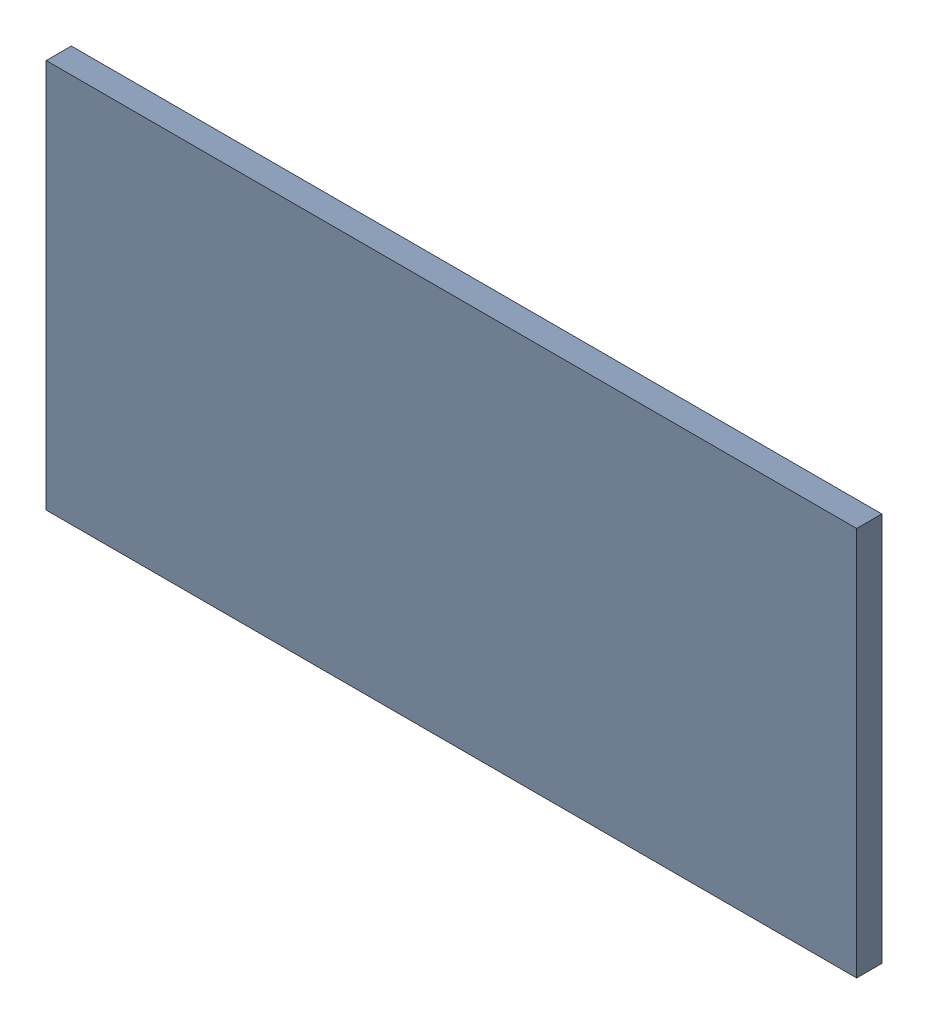
SolidWorks assembly Pad ADXL345-14(23.098mm,57mm) on Top Layer, configuration Predeterminado. Lengths in mm.
Overall size (1.14 0.55 0.04).
2 component instances, 1 part files, 0 mates.
Components (placement in the parent):
- Pad ADXL345-14(23.098mm,57mm) on Top Layer-1-1: Pad ADXL345-14(23.098mm,57mm) on Top Layer-1 [Predeterminado] at (-68.317 -44.187 -0.0457) size (1.14 0.55 0.04)
  - Pad ADXL345-14(23.098mm,57mm) on Top Layer-Part-1-1: Pad ADXL345-14(23.098mm,57mm) on Top Layer-Part-1 [Predeterminado] at origin size (1.14 0.55 0.04)
